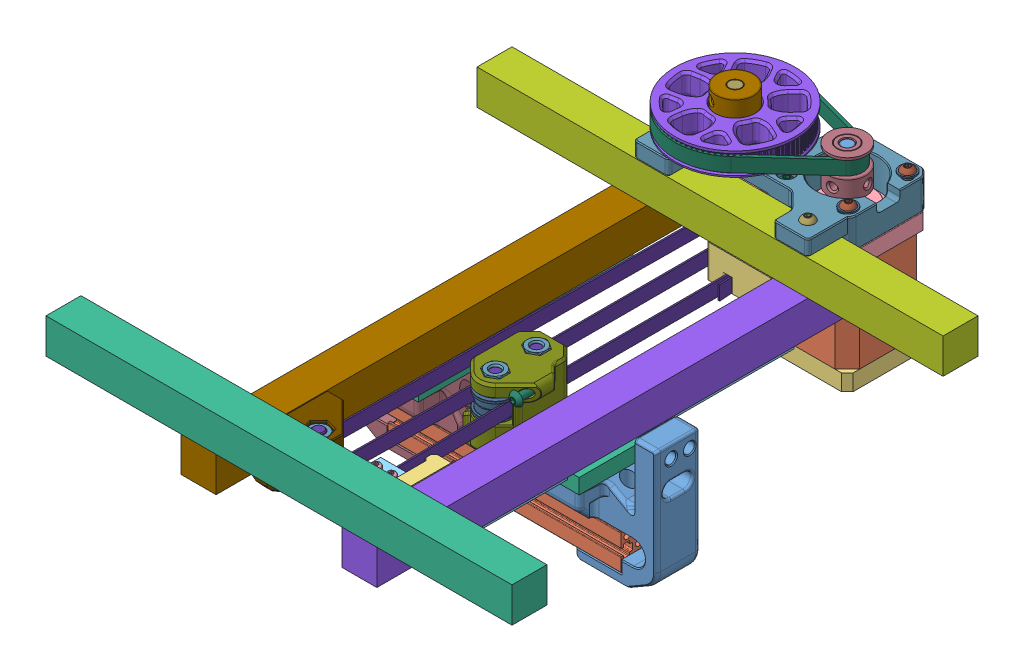
SolidWorks assembly Pulley_Z_Drive, configuration Default. Lengths in mm.
Overall size (200 98.55 245.11).
84 component instances, 40 part files, 0 mates.
Components (placement in the parent):
- Pulley_Z_Drive.step-1: Pulley_Z_Drive.step [Default] at origin size (200 98.55 245.11)
  - Nema14 _1_.step-1: Nema14 _1_.step [Default] at origin size (35 76 35)
    - nema14_eje.step-1: nema14_eje.step [Default] at (25.507 -33.4 -18.4) x (0 1 0) z (-0.343907 0 -0.939004) size (66 5 5)
    - nema14_centro.step-1: nema14_centro.step [Default] at (8.007 -16.4 -35.9) x (0 0 1) z (-1 0 0) size (35 38 35)
    - nema14_base.step-1: nema14_base.step [Default] at (8.007 -35.4 -35.9) x (0 0 1) z (-1 0 0) size (35 7 35)
    - nema14_techo.step-1: nema14_techo.step [Default] at (8.007 1.6 -35.9) x (0 0 1) z (-1 0 0) size (35 9 35)
  - MGN7_150mm_Z _1_.step-1: MGN7_150mm_Z _1_.step [Default] at origin size (86 8 150)
    - MGN7 Rail.step-1: MGN7 Rail.step [Default] at (69 0 0) size (7 4.8 150)
    - MGN7H.step-1: MGN7H.step [Default] at (69 0 66.402) size (17 6.5 30.8)
    - MGN7 Rail.step-2: MGN7 Rail.step [Default] at origin size (7 4.8 150)
    - MGN7H.step-2: MGN7H.step [Default] at (0 0 66.402) size (17 6.5 30.8)
  - Driven Gear _1_.step-1: Driven Gear _1_.step [Default] at origin size (68.71 60 68.71)
    - 80T Gear _1_.step-1: 80T Gear _1_.step [Default] at origin size (68.71 20.85 68.71)
      - M3x8 BHCS.step-1: M3x8 BHCS.step [Default] at (-9.7286 21.95 -2.6032) x (-0.904559 0 -0.426348) z (0 -1 0) size (5.7 5.7 9.65)
      - M3x8 BHCS.step-2: M3x8 BHCS.step [Default] at (-18.2386 21.95 -3.6837) x (-0.904559 0 -0.426348) z (0 -1 0) size (5.7 5.7 9.65)
      - M3x8 BHCS.step-3: M3x8 BHCS.step [Default] at (-12.3209 21.95 -16.2391) x (-0.904559 0 -0.426348) z (0 -1 0) size (5.7 5.7 9.65)
      - M3x8 BHCS.step-4: M3x8 BHCS.step [Default] at (-6.0712 21.95 -10.3628) x (-0.904559 0 -0.426348) z (0 -1 0) size (5.7 5.7 9.65)
      - 80T Gear v1.step-1: 80T Gear v1.step [Default] at (-13.2407 28.7007 -8.9999) x (-0.904559 0 -0.426348) z (0 1 0) size (51.63 51.63 14.4)
      - GT2 20T 6mm De-flanged.step-1: GT2 20T 6mm De-flanged.step [Default] at (-13.24 39.85 -9) x (0 -1 0) z (-0.904559 0 -0.426348) size (16 16 16)
      - M3x8 BHCS.step-5: M3x8 BHCS.step [Default] at (-19.8407 21.95 -12.1111) x (-0.904559 0 -0.426348) z (0 -1 0) size (5.7 5.7 9.65)
    - F695 2RS.step-1: F695 2RS.step [Default] at (-13.24 15 -9) size (15 4 15)
    - M5 Washer.step-1: M5 Washer.step [Default] at (-13.24 -0.65 -9) x (-0.426348 0 0.904559) z (0 1 0) size (9 9 1)
    - 5x60 Shaft.step-1: 5x60 Shaft.step [Default] at (0.5459 9.85 -17.1392) x (0.426348 0 -0.904559) z (0.904559 0 0.426348) size (5 60 5)
    - F695 2RS.step-2: F695 2RS.step [Default] at (-13.24 0.35 -9) size (15 4 15)
    - GT2 20T 6mm Powge v2.step-1: GT2 20T 6mm Powge v2.step [Default] at (-13.24 -0.65 -9) x (0 -1 0) z (0.426348 0 -0.904559) size (16 16 16)
  - Bed Holder _1_.step-1: Bed Holder _1_.step [Default] at origin size (38.08 41.92 35.32)
    - Hex nut grade A & B M5x0.8.step-1: Hex nut grade A & B M5x0.8.step [Default] at (0 -3.45 107.102) x (0 0 -1) z (0 1 0) size (9.26 9.28 4.74)
    - Socket button head screw M3x0.5 x 12.step-1: Socket button head screw M3x0.5 x 12.step [Default] at (-14 -29.35 95.702) x (1 0 0) z (0 1 0) size (5.7 5.7 13.65)
    - F695 2RS.step-1: F695 2RS.step [Default] at (0 -8 89.502) x (-0.235761 0 -0.971811) z (-0.971811 0 0.235761) size (15 4 15)
    - Socket button head screw M3x0.5 x 12.step-2: Socket button head screw M3x0.5 x 12.step [Default] at (14 -29.35 95.702) x (1 0 0) z (0 1 0) size (5.7 5.7 13.65)
    - F695 2RS.step-2: F695 2RS.step [Default] at (0 -16 107.102) x (0.985626 0 0.168941) z (-0.168941 0 0.985626) size (15 4 15)
    - Hex nut grade A & B M5x0.8.step-2: Hex nut grade A & B M5x0.8.step [Default] at (0 -3.45 89.502) x (0 0 -1) z (0 -1 0) size (9.26 9.28 4.74)
    - bed_mount.step-1: bed_mount.step [Default] at (0 0 66.002) size (38.08 38.75 32.8)
    - Socket button head screw M5x0.8 x 20.step-1: Socket button head screw M5x0.8 x 20.step [Default] at (0 -24.75 89.502) x (0 0 1) z (0 -1 0) size (9.5 9.5 22.75)
    - F695 2RS.step-3: F695 2RS.step [Default] at (0 -16 89.502) x (-0.235761 0 -0.971811) z (0.971811 0 -0.235761) size (15 4 15)
    - Socket button head screw M5x0.8 x 20.step-2: Socket button head screw M5x0.8 x 20.step [Default] at (0 -24.75 107.102) x (0 0 -1) z (0 -1 0) size (9.5 9.5 22.75)
    - Socket button head screw M3x0.5 x 12.step-3: Socket button head screw M3x0.5 x 12.step [Default] at (11.65 -5.1117 111.352) size (5.7 5.7 13.65)
    - F695 2RS.step-4: F695 2RS.step [Default] at (0 -8 107.102) x (0.985626 0 0.168941) z (0.168941 0 -0.985626) size (15 4 15)
  - Top Idler _1_.step-1: Top Idler _1_.step [Default] at origin size (24.94 22.75 32.8)
    - top_idler_base.step-1: top_idler_base.step [Default] at origin size (20.71 20 32.8)
    - Hex nut grade A & B M5x0.8.step-1: Hex nut grade A & B M5x0.8.step [Default] at (-14.38 -3.05 168.6) x (0.707107 0 -0.707107) z (0 1 0) size (9.26 9.28 4.74)
    - Socket button head screw M3x0.5 x 8.step-1: Socket button head screw M3x0.5 x 8.step [Default] at (-22.15 -7.5 180) x (0 0 1) z (1 0 0) size (5.7 5.7 9.65)
    - F695 2RS.step-1: F695 2RS.step [Default] at (-14.358 -16 168.578) size (15 4 15)
    - Socket button head screw M3x0.5 x 8.step-2: Socket button head screw M3x0.5 x 8.step [Default] at (-22.15 -7.5 157.2) x (0 0 1) z (1 0 0) size (5.7 5.7 9.65)
    - Socket button head screw M5x0.8 x 20.step-1: Socket button head screw M5x0.8 x 20.step [Default] at (-14.38 -22.75 168.6) x (0 0 1) z (0 -1 0) size (9.5 9.5 22.75)
    - F695 2RS.step-2: F695 2RS.step [Default] at (-14.358 -8 168.578) x (1 0 0) z (0 0 -1) size (15 4 15)
  - Top Endstop _1_.step-1: Top Endstop _1_.step [Default] at origin size (24.6 20 32.8)
    - Omron_D2F_F-1.step-1: Omron_D2F_F-1.step [Default] at (16.6994 -5.4631 169.0378) x (1 0 0) z (0 1 0) size (1.2 3.5 2.9)
    - Socket button head screw M3x0.5 x 8.step-1: Socket button head screw M3x0.5 x 8.step [Default] at (22.15 -7.5 156.2) x (0 -1 0) z (-1 0 0) size (5.7 5.7 9.65)
    - Socket button head screw M3x0.5 x 8.step-2: Socket button head screw M3x0.5 x 8.step [Default] at (22.15 -7.5 181) x (0 -1 0) z (-1 0 0) size (5.7 5.7 9.65)
    - upper_belt_end_holder.step-1: upper_belt_end_holder.step [Default] at origin size (20.69 20 32.8)
    - M2x10 self tapping screw for plastic-1.step-1: M2x10 self tapping screw for plastic-1.step [Default] at (10.35 -2.2 168.6) x (1 0 0) z (0 1 0) size (3.75 3.75 11.6)
    - M2x10 self tapping screw for plastic-1.step-2: M2x10 self tapping screw for plastic-1.step [Default] at (16.85 -2.2 168.6) x (1 0 0) z (0 1 0) size (3.75 3.75 11.6)
    - Omron_D2F_F-1-0.step-1: Omron_D2F_F-1-0.step [Default] at (16.85 -5.1 168.6) x (1 0 0) z (0 1 0) size (12.8 10 5.8)
  - id6.step-1: id6.step [Default] at origin size (200 15 15)
  - id11.step-1: id11.step [Default] at origin size (200 15 15)
  - id16.step-1: id16.step [Default] at origin size (15 15 200)
  - id21.step-1: id21.step [Default] at origin size (15 15 200)
  - Socket button head screw M3x0.5 x 8.step-1: Socket button head screw M3x0.5 x 8.step [Default] at (22.9 -5.65 7.5) x (1 0 0) z (0 -1 0) size (5.7 5.7 9.65)
  - M3 Washer.step-1: M3 Washer.step [Default] at (38.4551 21.6 -5.8662) x (0 0 -1) z (0 1 0) size (7 7 0.6)
  - Socket button head screw M3x0.5 x 12.step-1: Socket button head screw M3x0.5 x 12.step [Default] at (12.507 20.05 -5.4) x (1 0 0) z (0 1 0) size (5.7 5.7 13.65)
  - Socket button head screw M3x0.5 x 16.step-1: Socket button head screw M3x0.5 x 16.step [Default] at (1.341 3.75 -9) x (1 0 0) z (0 -1 0) size (5.7 5.7 17.65)
  - Socket button head screw M3x0.5 x 10.step-1: Socket button head screw M3x0.5 x 10.step [Default] at (-25.4055 23.25 7.5) x (1 0 0) z (0 1 0) size (5.7 5.7 11.65)
  - Rear_Bed_Mount_Left.step-1: Rear_Bed_Mount_Left.step [Default] at (-42.5 -51.5 83.202) x (-1 0 0) z (0 0 1) size (45.9 36.34 29.8)
  - motor_plate.step-1: motor_plate.step [Default] at origin size (76.01 13 51.87)
  - GT2 Belt 188mm.step-1: GT2 Belt 188mm.step [Default] at (-4.6017 -0.8179 -29.2457) x (-0.971811 0 0.235761) z (-0.235761 0 -0.971811) size (72.46 6 51.69)
  - M3 Washer.step-2: M3 Washer.step [Default] at (12.0409 21.6 -31.3481) x (0 0 -1) z (0 1 0) size (7 7 0.6)
  - M3 Threaded Insert.step-1: M3 Threaded Insert.step [Default] at (1.341 17.75 -9) x (1 0 0) z (0 1 0) size (5.04 5.04 3.89)
  - M3 Threaded Insert.step-2: M3 Threaded Insert.step [Default] at (-27.821 17.75 -9) x (1 0 0) z (0 1 0) size (5.04 5.04 3.89)
  - Z Belt.step-1: Z Belt.step [Default] at (-4.6042 -0.8179 -29.2467) x (-0.971782 0 0.235881) z (-0.235881 0 -0.971782) size (76.51 6 195.04)
  - Socket button head screw M3x0.5 x 16.step-2: Socket button head screw M3x0.5 x 16.step [Default] at (37.9923 23.85 -31.8178) x (0 0 -1) z (0 1 0) size (5.7 5.7 17.65)
  - Socket button head screw M3x0.5 x 10.step-2: Socket button head screw M3x0.5 x 10.step [Default] at (34.5 23.25 7.5) x (1 0 0) z (0 1 0) size (5.7 5.7 11.65)
  - Socket button head screw M3x0.5 x 20.step-1: Socket button head screw M3x0.5 x 20.step [Default] at (-22.44 7.5 -15.65) x (1 0 0) z (0 0 -1) size (5.7 5.7 21.65)
  - Socket button head screw M3x0.5 x 20.step-2: Socket button head screw M3x0.5 x 20.step [Default] at (-4.04 7.5 -15.65) x (1 0 0) z (0 0 -1) size (5.7 5.7 21.65)
  - Rear_Bed_Mount_Right.step-1: Rear_Bed_Mount_Right.step [Default] at (17.5 -51.5 83.202) x (-1 0 0) z (0 0 1) size (45.94 56.92 29.84)
  - Socket button head screw M3x0.5 x 8.step-2: Socket button head screw M3x0.5 x 8.step [Default] at (2.5 -5.65 7.5) x (1 0 0) z (0 -1 0) size (5.7 5.7 9.65)
  - Socket button head screw M3x0.5 x 16.step-3: Socket button head screw M3x0.5 x 16.step [Default] at (12.0409 23.85 -31.3481) x (0 0 -1) z (0 1 0) size (5.7 5.7 17.65)
  - Socket button head screw M3x0.5 x 16.step-4: Socket button head screw M3x0.5 x 16.step [Default] at (-27.821 3.75 -9) x (1 0 0) z (0 -1 0) size (5.7 5.7 17.65)
  - M3 Washer.step-3: M3 Washer.step [Default] at (37.9923 21.6 -31.8178) x (0 0 -1) z (0 1 0) size (7 7 0.6)
  - GT2 20T 6mm Powge v2.step-1: GT2 20T 6mm Powge v2.step [Default] at (25.507 16.95 -18.4) x (0 1 0) z (0.987217 0 -0.159382) size (16 16 16)
  - 1515 - 100mm-1.step-1: 1515 - 100mm-1.step [Default] at (0 -46.5 95.702) x (0 -1 0) z (-1 0 0) size (15 15 100)
  - lower_belt_end_holder.step-1: lower_belt_end_holder.step [Default] at origin size (28.4 15 15.03)
  - Socket button head screw M3x0.5 x 16.step-5: Socket button head screw M3x0.5 x 16.step [Default] at (38.4551 23.85 -5.8662) x (0 0 -1) z (0 1 0) size (5.7 5.7 17.65)
  - end_plate.step-1: end_plate.step [Default] at origin size (38.36 14.65 17.82)
